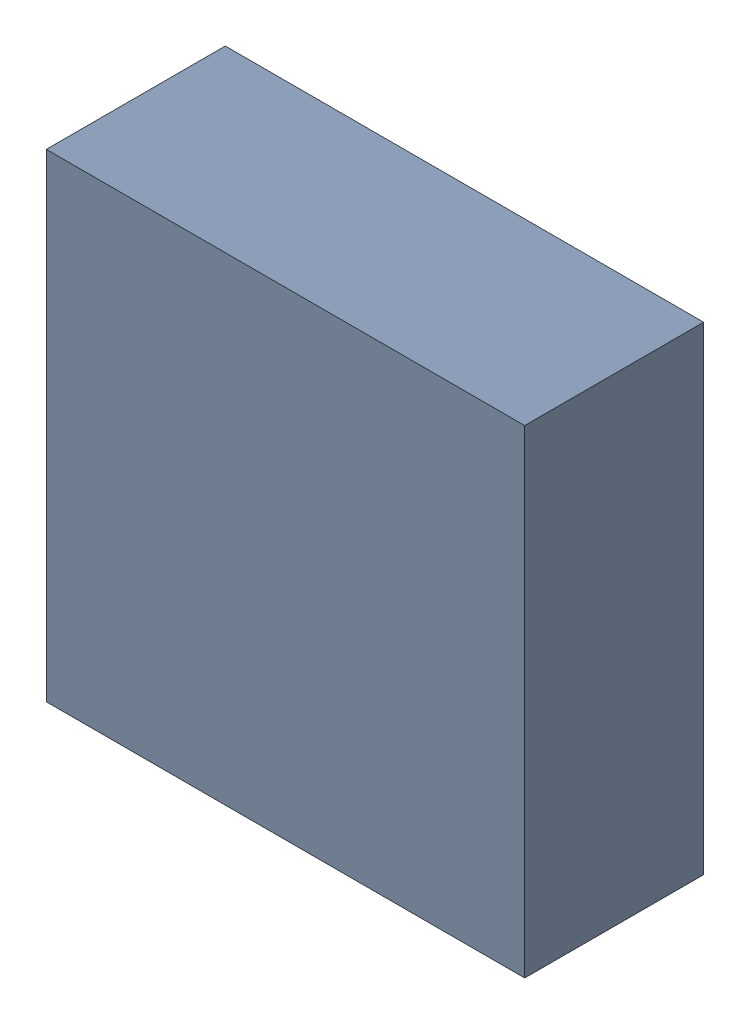
SolidWorks assembly U18, configuration ﾃﾞﾌｫﾙﾄ. Lengths in mm.
Overall size (1.47 1.47 0.55).
2 component instances, 1 part files, 0 mates.
Components (placement in the parent):
- 689262328-1: 689262328 [ﾃﾞﾌｫﾙﾄ] at (76.75 20.75 0) size (1.47 1.47 0.55)
  - Extruded_39-1: Extruded_39 [ﾃﾞﾌｫﾙﾄ] at origin size (1.47 1.47 0.55)
